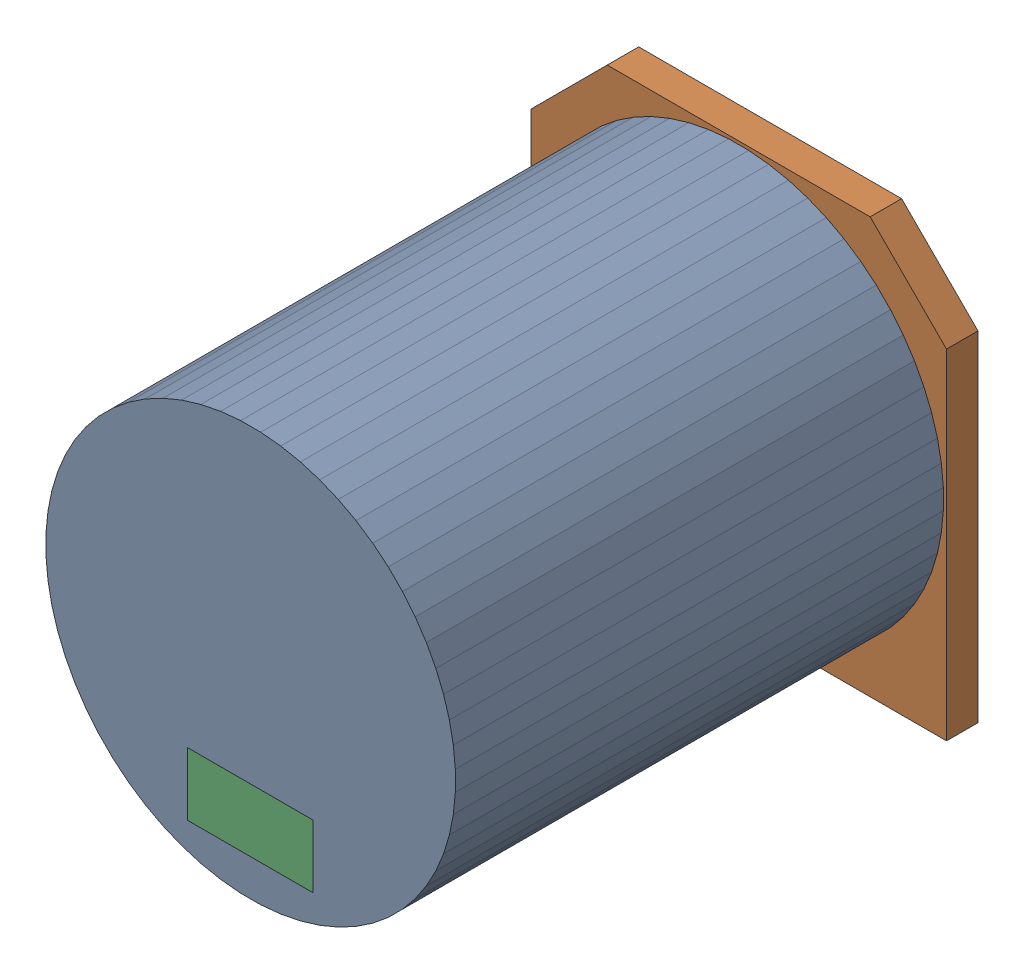
SolidWorks assembly C22, configuration Default. Lengths in mm.
Overall size (13.2 13.2 16.5).
6 component instances, 3 part files, 0 mates.
Components (placement in the parent):
- 6638397648-1: 6638397648 [Default] at (6.8703 52.8197 1) size (13 13 15.5)
  - Extruded-1: Extruded [Default] at origin size (13 13 15.5)
- 6638397568-1: 6638397568 [Default] at (6.8703 52.8197 0) size (13.2 13.2 1)
  - Extruded_2-1: Extruded_2 [Default] at origin size (13.2 13.2 1)
- 6638397808-1: 6638397808 [Default] at (6.858 48.482 16.4) size (4 2 0.1)
  - Extruded_3-1: Extruded_3 [Default] at origin size (4 2 0.1)
